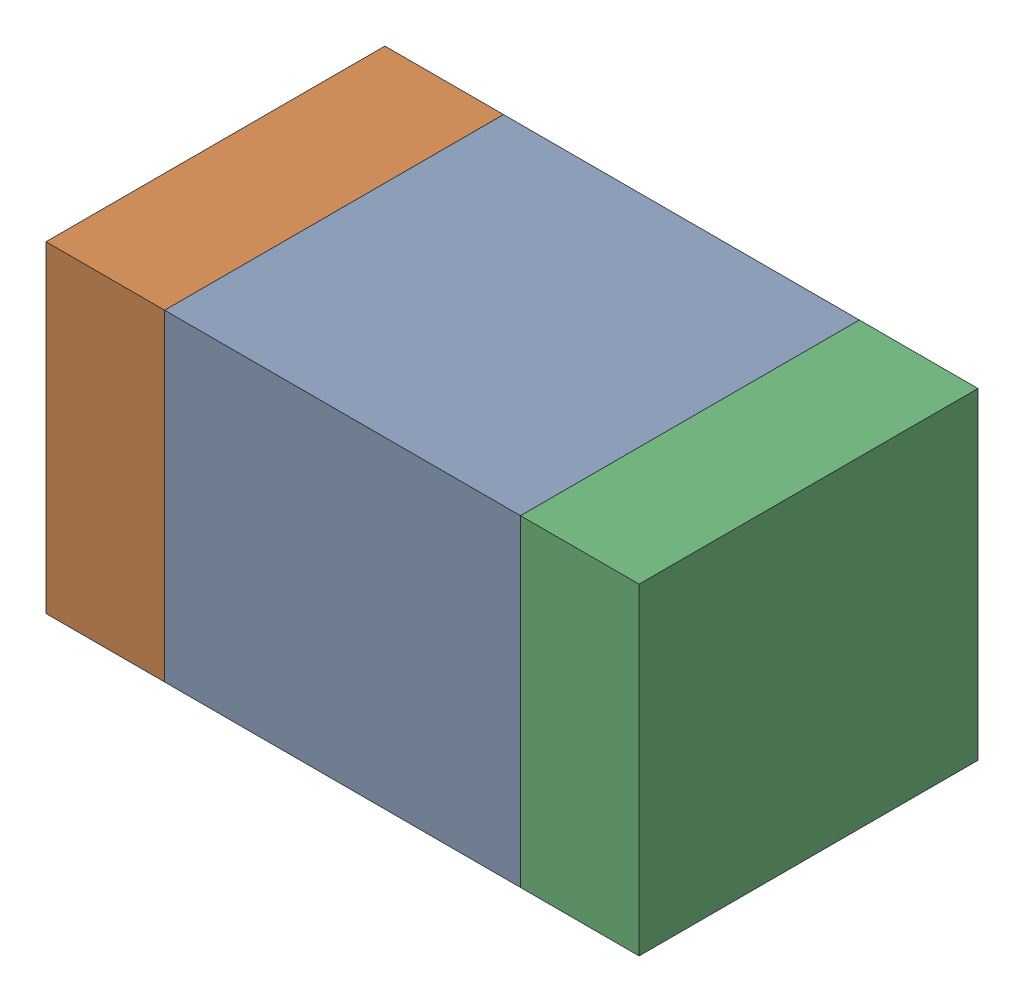
SolidWorks assembly C431PCB, configuration Default. Lengths in mm.
Overall size (1.75 0.95 1).
6 component instances, 2 part files, 0 mates.
Components (placement in the parent):
- 761616112-1: 761616112 [Default] at (117.3 110.2 -2.6638) size (1.05 0.95 1)
  - Extruded_14-1: Extruded_14 [Default] at origin size (1.05 0.95 1)
- 761616248-1: 761616248 [Default] at (116.6 110.2 -2.6638) size (0.35 0.95 1)
  - Extruded_15-1: Extruded_15 [Default] at origin size (0.35 0.95 1)
- 761616248-2: 761616248 [Default] at (118 110.2 -2.6638) size (0.35 0.95 1)
  - Extruded_15-1: Extruded_15 [Default] at origin size (0.35 0.95 1)
